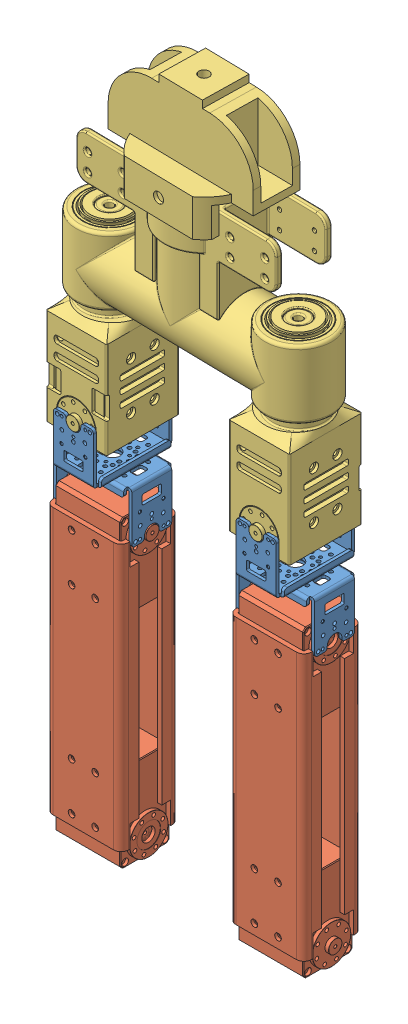
SolidWorks assembly URDF_TEST_SAMPLE_1, configuration Default. Lengths in mm.
Overall size (225.98 486.77 147.15).
5 component instances, 3 part files, 8 mates.
Components (placement in the parent):
- model_part_LINK-1: model_part_LINK [Default] at (-113.1556 -56.8734 -86.9554) x (0.999827 0 0.018597) z (-0.018597 0 0.999827) size (53.49 69 53.49)
- model_part_THIGH-1: model_part_THIGH [Default] at (257.7392 -39.4496 48.3825) x (-0.999827 -0.00471 -0.01799) z (0.018597 -0.253243 -0.967224) size (53.32 206.27 84.55)
- model_part_WAIST-1: model_part_WAIST [Default] at (-113.1556 -56.8734 -86.9554) x (0.999827 0 0.018597) z (-0.018597 0 0.999827) size (176.79 236.92 60.38)
- model_part_LINK-2: model_part_LINK [Default] at (12.8219 -56.8734 -84.5378) x (0.999827 0 0.018597) z (-0.018597 0 0.999827) size (53.49 69 53.49)
- model_part_THIGH-2: model_part_THIGH [Default] at (-239.1332 -39.4496 -117.0682) x (0.999827 -0.00471 0.01799) z (-0.018597 -0.253243 0.967224) size (53.32 206.27 84.55)
Mates (geometry in assembly coordinates):
- Concentric1: concentric anti-aligned: circle of model_part_LINK-1; circle of model_part_WAIST-1
- Coincident1: coincident anti-aligned: plane of model_part_LINK-1 through (-67.1857 93.3991 -60.0516) normal (0 0 1); plane of model_part_WAIST-1 through (-53.6857 123.3991 -60.0516) normal (0 0 -1)
- Concentric2: concentric anti-aligned: circle of model_part_LINK-1; circle of model_part_THIGH-2
- Coincident2: coincident anti-aligned: plane of model_part_LINK-1 through (-78.1857 89.3991 -49.0516) normal (1 0 0); plane of model_part_THIGH-2 through (-78.1857 59.3991 -35.5516) normal (-1 0 0)
- Concentric3: concentric anti-aligned: circle of model_part_WAIST-1; circle of model_part_LINK-2
- Coincident3: coincident anti-aligned: plane of model_part_WAIST-1 through (72.2918 123.3991 -57.6341) normal (0 0 -1); plane of model_part_LINK-2 through (58.7918 93.3991 -57.6341) normal (0 0 1)
- Concentric4: concentric anti-aligned: circle of model_part_THIGH-1; circle of model_part_LINK-2
- Coincident4: coincident anti-aligned: plane of model_part_THIGH-1 through (47.7918 59.3991 -33.1341) normal (-1 0 0); plane of model_part_LINK-2 through (47.7918 89.3991 -46.6341) normal (1 0 0)
